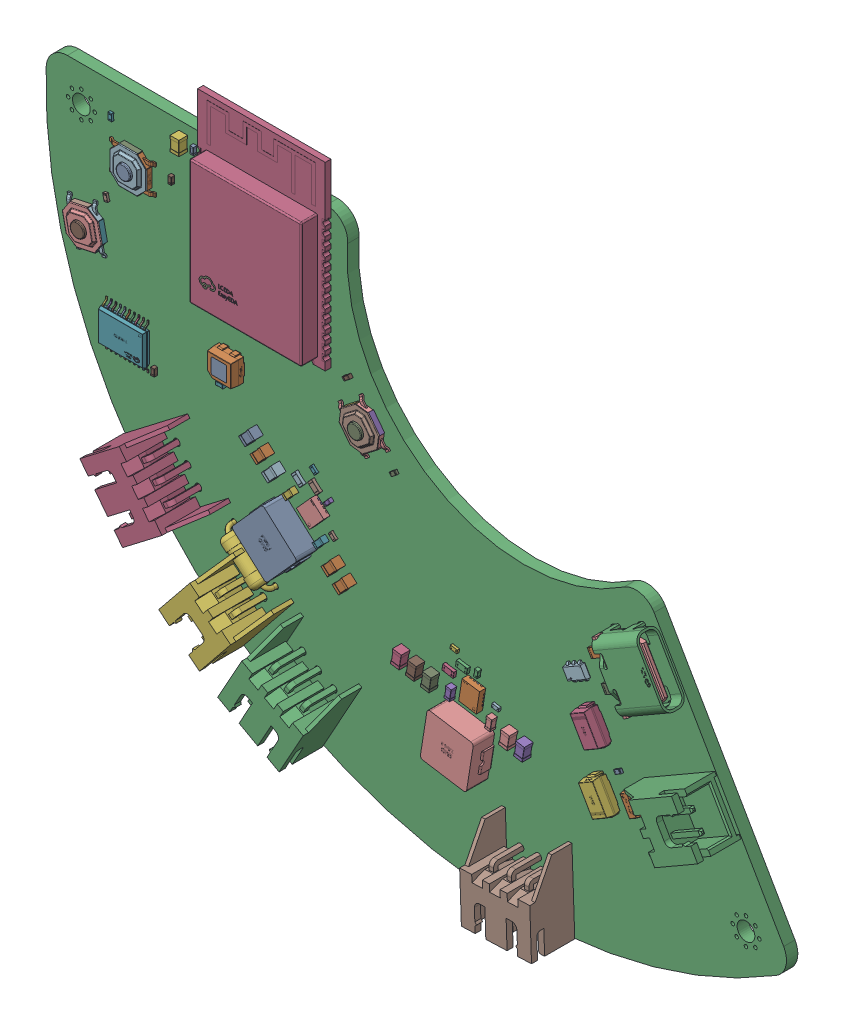
SolidWorks assembly head_control_board, configuration Default. Lengths in mm.
Overall size (104.47 78.47 9.5).
116 component instances, 20 part files, 0 mates.
Components (placement in the parent):
- head_control_board(2)-1: head_control_board(2) [Default] at origin size (104.47 78.47 9.5)
  - C_0402_1005Metric-1: C_0402_1005Metric [Default] at (-31.1333 33.9184 1.65) x (0 -1 0) z (0 0 1) size (1 0.5 0.5)
    - C_0402_1005Metric-0-1: C_0402_1005Metric-0 [Default] at origin size (1 0.5 0.5)
  - R_0805_2012Metric-1: R_0805_2012Metric [Default] at (25.7526 1.0179 1.65) x (0.866025 0.5 0) z (0 0 1) size (2 1.2 0.45)
    - R_0805_2012Metric-1-1: R_0805_2012Metric-1 [Default] at origin size (2 1.2 0.45)
  - JST_XH_S2B-XH-A-1_1x02_P2.50mm_Horizontal-1: JST_XH_S2B-XH-A-1_1x02_P2.50mm_Horizontal [Default] at (38.043 -13.5947 1.65) x (-0.5 0.866025 0) z (0 0 1) size (7.4 11.5 9.5)
    - JST_S2B_XH_A_1-1: JST_S2B_XH_A_1 [Default] at origin size (7.4 11.5 9.5)
  - C_0805_2012Metric-1: C_0805_2012Metric [Default] at (-1.5819 -13.0649 1.65) x (0.156434 0.987688 0) z (0 0 1) size (2 1.25 1.25)
    - C_0805_2012Metric-2-1: C_0805_2012Metric-2 [Default] at origin size (2 1.25 1.25)
  - KEY-SMD_4P-L5.2-W5.2-H1.5-LS6.4-P3.70-1: KEY-SMD_4P-L5.2-W5.2-H1.5-LS6.4-P3.70 [Default] at (-7.2414 12.0071 1.65) x (0.608761 -0.793353 0) z (0 0 1) size (6.4 5.2 1.55)
    - KEY-SMD_4P-L5.2-W5.2-H1.5-LS6.4-P3.70-3-1: KEY-SMD_4P-L5.2-W5.2-H1.5-LS6.4-P3.70-3 [Default] at origin size (6.4 5.2 1.55)
  - C_0805_2012Metric-2: C_0805_2012Metric [Default] at (0.5181 -13.4149 1.65) x (0.156434 0.987688 0) z (0 0 1) size (2 1.25 1.25)
    - C_0805_2012Metric-2-1: C_0805_2012Metric-2 [Default] at origin size (2 1.25 1.25)
  - SOT-457_L2.9-W1.5-H1.1-P0.95-LS2.8-BL-1: SOT-457_L2.9-W1.5-H1.1-P0.95-LS2.8-BL [Default] at (22.863 -2.9021 1.65) x (-0.866025 -0.5 0) z (0 0 1) size (3.1 3 1.2)
    - SOT-457_L2.9-W1.5-H1.1-P0.95-LS2.8-BL-4-1: SOT-457_L2.9-W1.5-H1.1-P0.95-LS2.8-BL-4 [Default] at origin size (3.1 3 1.2)
  - C_0805_2012Metric-3: C_0805_2012Metric [Default] at (-9.4429 -8.0985 1.65) x (0.669131 0.743145 0) z (0 0 1) size (2 1.25 1.25)
    - C_0805_2012Metric-2-1: C_0805_2012Metric-2 [Default] at origin size (2 1.25 1.25)
  - C_0402_1005Metric-2: C_0402_1005Metric [Default] at (8.9418 -9.9525 1.65) x (0.156434 0.987688 0) z (0 0 1) size (1 0.5 0.5)
    - C_0402_1005Metric-0-1: C_0402_1005Metric-0 [Default] at origin size (1 0.5 0.5)
  - R_0603_1608Metric-1: R_0603_1608Metric [Default] at (4.9519 -11.6475 1.65) x (-0.987688 0.156434 0) z (0 0 1) size (1.6 0.8 0.45)
    - R_0603_1608Metric-5-1: R_0603_1608Metric-5 [Default] at origin size (1.6 0.8 0.45)
  - C_0603_1608Metric-1: C_0603_1608Metric [Default] at (5.2667 -14.0766 1.65) x (0.156434 0.987688 0) z (0 0 1) size (1.6 0.8 0.8)
    - C_0603_1608Metric-6-1: C_0603_1608Metric-6 [Default] at origin size (1.6 0.8 0.8)
  - SMA_L4.3-W2.6-LS5.2-RD-1: SMA_L4.3-W2.6-LS5.2-RD [Default] at (26.9015 -15.6971 1.65) x (-0.5 0.866025 0) z (0 0 1) size (4.7 2.6 2.1)
    - SMA_L4.3-W2.6-LS5.2-RD-7-1: SMA_L4.3-W2.6-LS5.2-RD-7 [Default] at origin size (4.7 2.6 2.1)
  - JST_XH_S3B-XH-A-1_1x03_P2.50mm_Horizontal-1: JST_XH_S3B-XH-A-1_1x03_P2.50mm_Horizontal [Default] at (14.7037 -28.5079 1.65) x (0.999391 0.034899 0) z (0 0 1) size (9.9 11.5 9.5)
    - JST_S3B_XH_A_1-1: JST_S3B_XH_A_1 [Default] at origin size (9.9 11.5 9.5)
  - R_0805_2012Metric-2: R_0805_2012Metric [Default] at (27.7276 -2.4029 1.65) x (0.866025 0.5 0) z (0 0 1) size (2 1.2 0.45)
    - R_0805_2012Metric-1-1: R_0805_2012Metric-1 [Default] at origin size (2 1.2 0.45)
  - C_0603_1608Metric-2: C_0603_1608Metric [Default] at (10.9917 -14.894 1.65) x (0.156434 0.987688 0) z (0 0 1) size (1.6 0.8 0.8)
    - C_0603_1608Metric-6-1: C_0603_1608Metric-6 [Default] at origin size (1.6 0.8 0.8)
  - C_0402_1005Metric-3: C_0402_1005Metric [Default] at (-36.6583 4.1034 1.65) x (0 -1 0) z (0 0 1) size (1 0.5 0.5)
    - C_0402_1005Metric-0-1: C_0402_1005Metric-0 [Default] at origin size (1 0.5 0.5)
  - R_0603_1608Metric-2: R_0603_1608Metric [Default] at (-16.2964 1.1254 1.65) x (-0.743145 0.669131 0) z (0 0 1) size (1.6 0.8 0.45)
    - R_0603_1608Metric-5-1: R_0603_1608Metric-5 [Default] at origin size (1.6 0.8 0.45)
  - R_0402_1005Metric-1: R_0402_1005Metric [Default] at (28.7584 -12.0966 1.65) x (0.866025 0.5 0) z (0 0 1) size (1 0.5 0.35)
    - R_0402_1005Metric-8-1: R_0402_1005Metric-8 [Default] at origin size (1 0.5 0.35)
  - C_0805_2012Metric-4: C_0805_2012Metric [Default] at (-21.0333 2.0234 1.65) x (0.669131 0.743145 0) z (0 0 1) size (2 1.25 1.25)
    - C_0805_2012Metric-2-1: C_0805_2012Metric-2 [Default] at origin size (2 1.25 1.25)
  - JST_XH_S3B-XH-A-1_1x03_P2.50mm_Horizontal-2: JST_XH_S3B-XH-A-1_1x03_P2.50mm_Horizontal [Default] at (-16.0229 -19.9395 1.65) x (0.87462 -0.48481 0) z (0 0 1) size (9.9 11.5 9.5)
    - JST_S3B_XH_A_1-1: JST_S3B_XH_A_1 [Default] at origin size (9.9 11.5 9.5)
  - JST_XH_S3B-XH-A-1_1x03_P2.50mm_Horizontal-3: JST_XH_S3B-XH-A-1_1x03_P2.50mm_Horizontal [Default] at (-33.7771 -3.3028 1.65) x (0.608761 -0.793353 0) z (0 0 1) size (9.9 11.5 9.5)
    - JST_S3B_XH_A_1-1: JST_S3B_XH_A_1 [Default] at origin size (9.9 11.5 9.5)
  - C_0805_2012Metric-5: C_0805_2012Metric [Default] at (15.782 -15.6527 1.65) x (0.156434 0.987688 0) z (0 0 1) size (2 1.25 1.25)
    - C_0805_2012Metric-2-1: C_0805_2012Metric-2 [Default] at origin size (2 1.25 1.25)
  - C_0603_1608Metric-3: C_0603_1608Metric [Default] at (-17.3333 -1.0766 1.65) x (0.669131 0.743145 0) z (0 0 1) size (1.6 0.8 0.8)
    - C_0603_1608Metric-6-1: C_0603_1608Metric-6 [Default] at origin size (1.6 0.8 0.8)
  - R_0402_1005Metric-2: R_0402_1005Metric [Default] at (-42.8333 32.1134 1.65) x (0 -1 0) z (0 0 1) size (1 0.5 0.35)
    - R_0402_1005Metric-8-1: R_0402_1005Metric-8 [Default] at origin size (1 0.5 0.35)
  - R_0603_1608Metric-3: R_0603_1608Metric [Default] at (-13.9833 1.3234 1.65) x (-0.743145 0.669131 0) z (0 0 1) size (1.6 0.8 0.45)
    - R_0603_1608Metric-5-1: R_0603_1608Metric-5 [Default] at origin size (1.6 0.8 0.45)
  - KEY-SMD_4P-L5.2-W5.2-H1.5-LS6.4-P3.70-2: KEY-SMD_4P-L5.2-W5.2-H1.5-LS6.4-P3.70 [Default] at (-39.8333 27.3534 1.65) size (6.4 5.2 1.55)
    - KEY-SMD_4P-L5.2-W5.2-H1.5-LS6.4-P3.70-3-1: KEY-SMD_4P-L5.2-W5.2-H1.5-LS6.4-P3.70-3 [Default] at origin size (6.4 5.2 1.55)
  - USB-C-SMD_TYPE-C-6PIN-2MD-073-1: USB-C-SMD_TYPE-C-6PIN-2MD-073 [Default] at (33.0237 2.963 3.33) x (-0.5 0.866025 0) z (0 0 1) size (8.95 7.58 4.16)
    - USB-C-SMD_TYPE-C-6PIN-2MD-073-9-1: USB-C-SMD_TYPE-C-6PIN-2MD-073-9 [Default] at origin size (8.95 7.58 4.16)
  - JST_XH_S2B-XH-A-1_1x02_P2.50mm_Horizontal-2: JST_XH_S2B-XH-A-1_1x02_P2.50mm_Horizontal [Default] at (-23.4914 -14.4929 1.65) x (0.777146 -0.62932 0) z (0 0 1) size (7.4 11.5 9.5)
    - JST_S2B_XH_A_1-1: JST_S2B_XH_A_1 [Default] at origin size (7.4 11.5 9.5)
  - C_0402_1005Metric-4: C_0402_1005Metric [Default] at (-27.2414 7.2321 1.65) x (-1 0 0) z (0 0 1) size (1 0.5 0.5)
    - C_0402_1005Metric-0-1: C_0402_1005Metric-0 [Default] at origin size (1 0.5 0.5)
  - R_0402_1005Metric-3: R_0402_1005Metric [Default] at (-43.4893 21.9223 1.65) x (-0.207912 0.978148 0) z (0 0 1) size (1 0.5 0.35)
    - R_0402_1005Metric-8-1: R_0402_1005Metric-8 [Default] at origin size (1 0.5 0.35)
  - R_0402_1005Metric-4: R_0402_1005Metric [Default] at (-2.8879 8.5129 1.65) x (-0.793353 -0.608761 0) z (0 0 1) size (1 0.5 0.35)
    - R_0402_1005Metric-8-1: R_0402_1005Metric-8 [Default] at origin size (1 0.5 0.35)
  - IND-SMD_L7.0-W6.6-H3.0-1: IND-SMD_L7.0-W6.6-H3.0 [Default] at (7.4599 -18.8148 1.65) x (-0.987688 0.156434 0) z (0 0 1) size (7.01 6.6 3.1)
    - IND-SMD_L7.0-W6.6-H3.0-10-1: IND-SMD_L7.0-W6.6-H3.0-10 [Default] at origin size (7.01 6.6 3.1)
  - C_0402_1005Metric-5: C_0402_1005Metric [Default] at (-34.2583 28.7234 1.65) x (0 1 0) z (0 0 1) size (1 0.5 0.5)
    - C_0402_1005Metric-0-1: C_0402_1005Metric-0 [Default] at origin size (1 0.5 0.5)
  - VQFN-HR-15_L3.0-W2.5-H0.9-P0.50-BL_TPS63070RNMR-1: VQFN-HR-15_L3.0-W2.5-H0.9-P0.50-BL_TPS63070RNMR [Default] at (8.4102 -12.7623 1.65) x (-0.987688 0.156434 0) z (0 0 1) size (2.5 3 0.9)
    - VQFN-HR-15_L3.0-W2.5-H0.9-P0.50-BL_TPS63070RNMR-11-1: VQFN-HR-15_L3.0-W2.5-H0.9-P0.50-BL_TPS63070RNMR-11 [Default] at origin size (2.5 3 0.9)
  - SMA_L4.3-W2.6-LS5.2-RD-2: SMA_L4.3-W2.6-LS5.2-RD [Default] at (25.713 -7.8385 1.65) x (0.5 -0.866025 0) z (0 0 1) size (4.7 2.6 2.1)
    - SMA_L4.3-W2.6-LS5.2-RD-7-1: SMA_L4.3-W2.6-LS5.2-RD-7 [Default] at origin size (4.7 2.6 2.1)
  - R_Axial_DIN0207_L6.3mm_D2.5mm_P7.62mm_Horizontal-1: R_Axial_DIN0207_L6.3mm_D2.5mm_P7.62mm_Horizontal [Default] at (-25.6833 -9.0016 1.65) x (0.766044 -0.642788 0) z (0 0 1) size (8.22 2.5 5.5)
    - R_Axial_DIN0207_L63mm_D25mm_P762mm_Horizontal-1: R_Axial_DIN0207_L63mm_D25mm_P762mm_Horizontal [Default] at origin size (8.22 2.5 5.5)
  - TSSOP-20_L6.5-W4.4-H1.0-LS6.4-P0.65-1: TSSOP-20_L6.5-W4.4-H1.0-LS6.4-P0.65 [Default] at (-40.6464 6.4771 1.65) x (0 -1 0) z (0 0 1) size (6.41 6.5 1.05)
    - TSSOP-20_L6.5-W4.4-H1.0-LS6.4-P0.65-12-1: TSSOP-20_L6.5-W4.4-H1.0-LS6.4-P0.65-12 [Default] at origin size (6.41 6.5 1.05)
  - C_0402_1005Metric-6: C_0402_1005Metric [Default] at (-12.0621 0.4301 1.65) x (0.669131 0.743145 0) z (0 0 1) size (1 0.5 0.5)
    - C_0402_1005Metric-0-1: C_0402_1005Metric-0 [Default] at origin size (1 0.5 0.5)
  - C_0805_2012Metric-6: C_0805_2012Metric [Default] at (-32.8083 34.0225 1.65) x (0 -1 0) z (0 0 1) size (2 1.25 1.25)
    - C_0805_2012Metric-2-1: C_0805_2012Metric-2 [Default] at origin size (2 1.25 1.25)
  - C_0603_1608Metric-4: C_0603_1608Metric [Default] at (-13.0286 -4.87 1.65) x (0.669131 0.743145 0) z (0 0 1) size (1.6 0.8 0.8)
    - C_0603_1608Metric-6-1: C_0603_1608Metric-6 [Default] at origin size (1.6 0.8 0.8)
  - VQFN-HR-15_L3.0-W2.5-H0.9-P0.50-BL_TPS63070RNMR-2: VQFN-HR-15_L3.0-W2.5-H0.9-P0.50-BL_TPS63070RNMR [Default] at (-14.0242 -1.6792 1.65) x (-0.743145 0.669131 0) z (0 0 1) size (2.5 3 0.9)
    - VQFN-HR-15_L3.0-W2.5-H0.9-P0.50-BL_TPS63070RNMR-11-1: VQFN-HR-15_L3.0-W2.5-H0.9-P0.50-BL_TPS63070RNMR-11 [Default] at origin size (2.5 3 0.9)
  - C_0805_2012Metric-7: C_0805_2012Metric [Default] at (-19.4333 0.5734 1.65) x (0.669131 0.743145 0) z (0 0 1) size (2 1.25 1.25)
    - C_0805_2012Metric-2-1: C_0805_2012Metric-2 [Default] at origin size (2 1.25 1.25)
  - C_0805_2012Metric-8: C_0805_2012Metric [Default] at (-22.6333 3.4234 1.65) x (0.669131 0.743145 0) z (0 0 1) size (2 1.25 1.25)
    - C_0805_2012Metric-2-1: C_0805_2012Metric-2 [Default] at origin size (2 1.25 1.25)
  - SOT-23-3P_L2.9-W1.3-H1.0-LS2.4-P0.95-1: SOT-23-3P_L2.9-W1.3-H1.0-LS2.4-P0.95 [Default] at (31.0339 -14.7546 1.65) x (0.866025 0.5 0) z (0 0 1) size (2.51 2.9 1.05)
    - SOT-23-3P_L2.9-W1.3-H1.0-LS2.4-P0.95-13-1: SOT-23-3P_L2.9-W1.3-H1.0-LS2.4-P0.95-13 [Default] at origin size (2.51 2.9 1.05)
  - KEY-SMD_4P-L5.2-W5.2-H1.5-LS6.4-P3.70-3: KEY-SMD_4P-L5.2-W5.2-H1.5-LS6.4-P3.70 [Default] at (-46.3174 17.0825 1.65) x (0.207912 -0.978148 0) z (0 0 1) size (6.4 5.2 1.55)
    - KEY-SMD_4P-L5.2-W5.2-H1.5-LS6.4-P3.70-3-1: KEY-SMD_4P-L5.2-W5.2-H1.5-LS6.4-P3.70-3 [Default] at origin size (6.4 5.2 1.55)
  - IND-SMD_L7.0-W6.6-H3.0-2: IND-SMD_L7.0-W6.6-H3.0 [Default] at (-18.2824 -6.4054 1.65) x (-0.743145 0.669131 0) z (0 0 1) size (7.01 6.6 3.1)
    - IND-SMD_L7.0-W6.6-H3.0-10-1: IND-SMD_L7.0-W6.6-H3.0-10 [Default] at origin size (7.01 6.6 3.1)
  - C_0805_2012Metric-9: C_0805_2012Metric [Default] at (-11.0221 -6.6766 1.65) x (0.669131 0.743145 0) z (0 0 1) size (2 1.25 1.25)
    - C_0805_2012Metric-2-1: C_0805_2012Metric-2 [Default] at origin size (2 1.25 1.25)
  - R_0603_1608Metric-4: R_0603_1608Metric [Default] at (6.8667 -10.2266 1.65) x (-0.987688 0.156434 0) z (0 0 1) size (1.6 0.8 0.45)
    - R_0603_1608Metric-5-1: R_0603_1608Metric-5 [Default] at origin size (1.6 0.8 0.45)
  - WIRELM-SMD_ESP32-S3-WROOM-1-1: WIRELM-SMD_ESP32-S3-WROOM-1 [Default] at (-20.9833 29.4704 1.65) size (18 25.5 3.11)
    - WIRELM-SMD_ESP32-S3-WROOM-1-14-1: WIRELM-SMD_ESP32-S3-WROOM-1-14 [Default] at origin size (18 25.5 3.11)
  - R_0402_1005Metric-5: R_0402_1005Metric [Default] at (5.6667 -8.6766 1.65) x (0.987688 -0.156434 0) z (0 0 1) size (1 0.5 0.35)
    - R_0402_1005Metric-8-1: R_0402_1005Metric-8 [Default] at origin size (1 0.5 0.35)
  - R_0402_1005Metric-6: R_0402_1005Metric [Default] at (-14.1833 3.2734 1.65) x (0.743145 -0.669131 0) z (0 0 1) size (1 0.5 0.35)
    - R_0402_1005Metric-8-1: R_0402_1005Metric-8 [Default] at origin size (1 0.5 0.35)
  - R_0402_1005Metric-7: R_0402_1005Metric [Default] at (-11.4896 -3.4971 1.65) x (-0.743145 0.669131 0) z (0 0 1) size (1 0.5 0.35)
    - R_0402_1005Metric-8-1: R_0402_1005Metric-8 [Default] at origin size (1 0.5 0.35)
  - C_0805_2012Metric-10: C_0805_2012Metric [Default] at (2.6181 -13.7649 1.65) x (0.156434 0.987688 0) z (0 0 1) size (2 1.25 1.25)
    - C_0805_2012Metric-2-1: C_0805_2012Metric-2 [Default] at origin size (2 1.25 1.25)
  - C_0805_2012Metric-11: C_0805_2012Metric [Default] at (13.6584 -15.3164 1.65) x (0.156434 0.987688 0) z (0 0 1) size (2 1.25 1.25)
    - C_0805_2012Metric-2-1: C_0805_2012Metric-2 [Default] at origin size (2 1.25 1.25)
  - C_0402_1005Metric-7: C_0402_1005Metric [Default] at (-9.3775 17.0156 1.65) x (-0.793353 -0.608761 0) z (0 0 1) size (1 0.5 0.5)
    - C_0402_1005Metric-0-1: C_0402_1005Metric-0 [Default] at origin size (1 0.5 0.5)
  - R_0402_1005Metric-8: R_0402_1005Metric [Default] at (11.5237 -12.8774 1.65) x (-0.987688 0.156434 0) z (0 0 1) size (1 0.5 0.35)
    - R_0402_1005Metric-8-1: R_0402_1005Metric-8 [Default] at origin size (1 0.5 0.35)
  - LED3535-4P_L3.5-W3.5-H1.9-LS3.7-1: LED3535-4P_L3.5-W3.5-H1.9-LS3.7 [Default] at (-25.8764 10.4671 1.65) x (0 1 0) z (0 0 1) size (3.5 3.51 1.94)
    - LED3535-4P_L3.5-W3.5-H1.9-LS3.7-15-1: LED3535-4P_L3.5-W3.5-H1.9-LS3.7-15 [Default] at origin size (3.5 3.51 1.94)
  - head_control_board_PCB-1: head_control_board_PCB [Default] at origin size (104.47 72.5 1.6)
